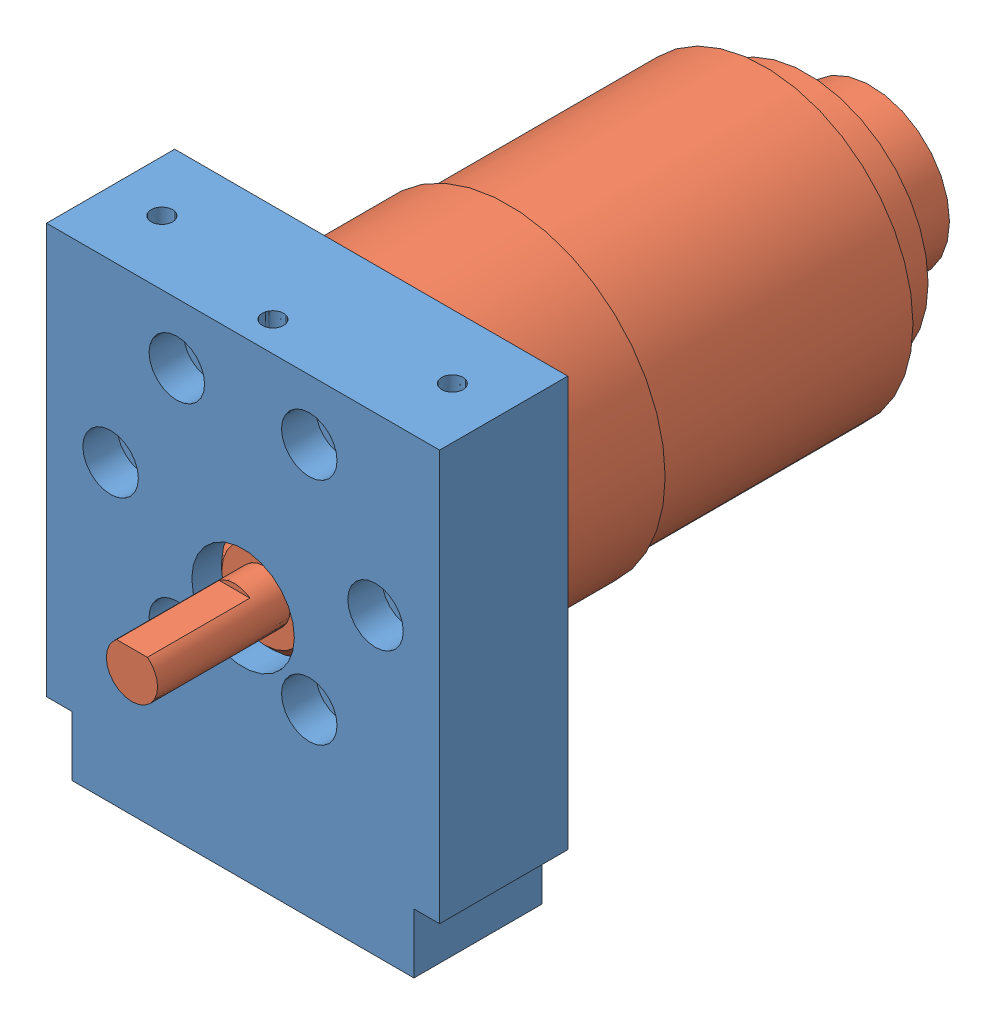
SolidWorks assembly motor-mount-assembly, configuration Default. Lengths in mm.
Overall size (46 55 86.5).
2 component instances, 2 part files, 3 mates.
Components (placement in the parent):
- mount-1: mount [Default] at (-12.0528 -11.3743 9.0876) size (46 55 15)
- gearnotor_w_encoder-1: gearnotor_w_encoder [Default] at (-12.0528 -4.3743 -6.9124) size (36.8 36.8 86.5)
Mates (geometry in assembly coordinates):
- Concentric1: concentric aligned: cylinder of mount-1 through (-12.0528 -11.3743 24.0876) axis (0 0 -1) radius 6; cylinder of gearnotor_w_encoder-1 through (-12.0528 -11.3743 21.5876) axis (0 0 -1) radius 6
- Coincident1: coincident anti-aligned: plane of mount-1 through (-12.0528 -4.3743 15.0876) normal (0 0 -1); plane of gearnotor_w_encoder-1 through (-12.0528 -4.3743 15.0876) normal (0 0 1)
- Concentric2: concentric anti-aligned: cylinder of mount-1 through (-4.3028 9.0491 24.0876) axis (0 0 -1) radius 1.5; cylinder of gearnotor_w_encoder-1 through (-4.3028 9.0491 10.0876) axis (0 0 1) radius 1.5
